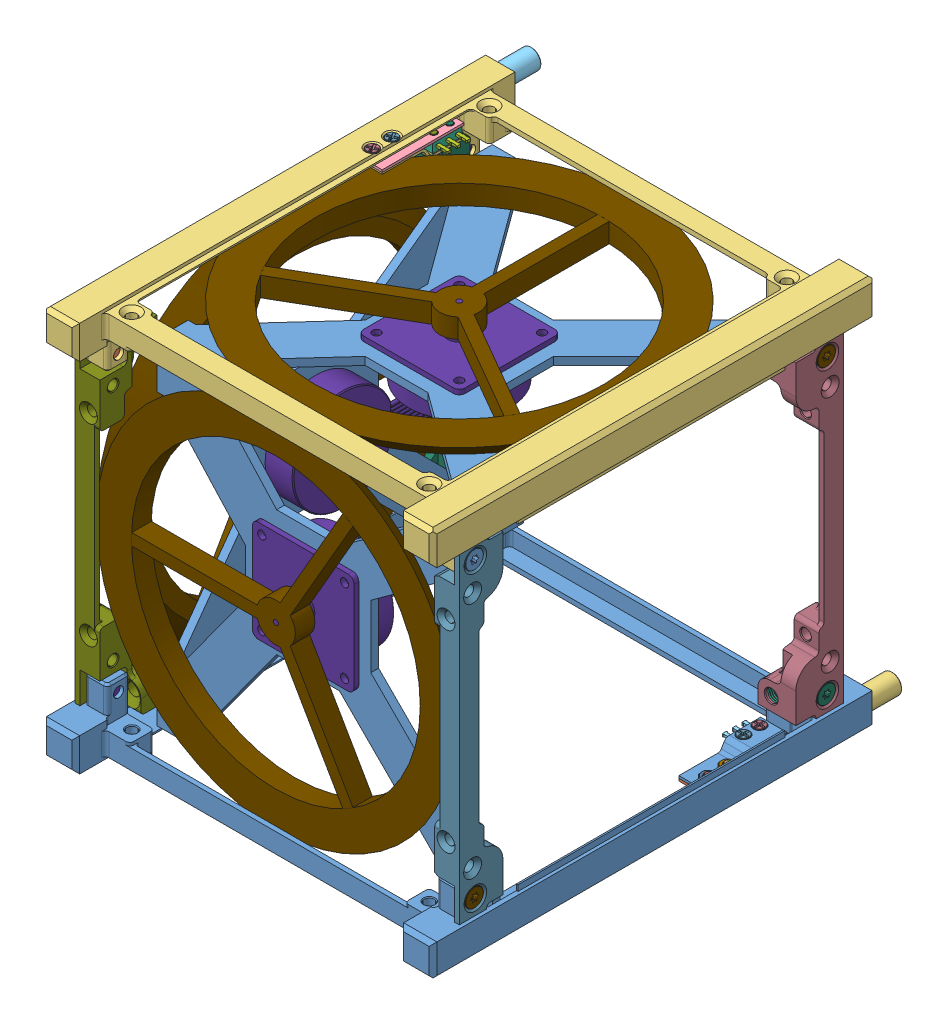
SolidWorks assembly 3dv1, configuration Default. Lengths in mm.
Overall size (100 100.02 121.5).
74 component instances, 55 part files, 12 mates.
Components (placement in the parent):
- isis_cubesat_sts_pc104_skeleton_asm-1: isis_cubesat_sts_pc104_skeleton_asm [Default] at (-72.5006 48.6232 32.8125) size (100 100.02 121.5)
  - INTEGRATED_SIDE_FRAME_007B-1: INTEGRATED_SIDE_FRAME_007B [Default] at origin size (100 15.41 121.5)
    - BRACKET_KS_007A-1: BRACKET_KS_007A [Default] at origin size (7.5 3.1 20.94)
    - BRACKET_KS_007B-1: BRACKET_KS_007B [Default] at origin size (7.5 0.6 20.94)
    - BUSJE_001-1: BUSJE_001 [Default] at origin size (5.05 5.05 11.8)
    - KILL_SWITCH_AV46J-1: KILL_SWITCH_AV46J [Default] at origin size (9.6 2.5 7.5)
      - KILL_SWITCH_BODY-1: KILL_SWITCH_BODY [Default] at origin size (6.6 2.5 7.5)
      - KILL_SWITCH_PINS-1: KILL_SWITCH_PINS [Default] at origin size (3.2 0.6 6.2)
    - KILL_SWITCH_LEVER-1: KILL_SWITCH_LEVER [Default] at origin size (4.59 2.4 6)
    - KILL_SWITCH_PIN-1: KILL_SWITCH_PIN [Default] at origin size (3.4 3.4 26.01)
    - KILL_SWITCH_SWITCH-1: KILL_SWITCH_SWITCH [Default] at origin size (2 1 1.2)
    - KS_MECH_SCREWS-1: KS_MECH_SCREWS [Default] at origin size (6.66 5 19.8)
      - NUT_M1_6-1: NUT_M1_6 [Default] at origin size (3.71 1.31 3.71)
      - NUT_M1_6_1-1: NUT_M1_6_1 [Default] at origin size (3.71 1.31 3.71)
      - SCREW_M1_6X4-1: SCREW_M1_6X4 [Default] at origin size (3 4.01 3)
      - SCREW_M1_6X4_1-1: SCREW_M1_6X4_1 [Default] at origin size (3 4.01 3)
      - SCREW_M1_6X4_2-1: SCREW_M1_6X4_2 [Default] at origin size (3 4.01 3)
      - SCREW_M1_6X4_3-1: SCREW_M1_6X4_3 [Default] at origin size (3 4.01 3)
    - SCREW_M2_5X6-1: SCREW_M2_5X6 [Default] at origin size (6.01 4.71 4.71)
    - SCREW_M2_5X6_1-1: SCREW_M2_5X6_1 [Default] at origin size (6.01 4.71 4.71)
    - SCREW_M2_5X6_2-1: SCREW_M2_5X6_2 [Default] at origin size (6.01 4.71 4.71)
    - SCREW_M2_5X6_3-1: SCREW_M2_5X6_3 [Default] at origin size (6.01 4.71 4.71)
    - SIDE_FRAME_007-1: SIDE_FRAME_007 [Default] at origin size (100 15.41 113.51)
    - SPRING_02-1: SPRING_02 [Default] at origin size (3.78 3.8 18.32)
  - INTEGRATED_SIDE_FRAME_007B_1-1: INTEGRATED_SIDE_FRAME_007B_1 [Default] at origin size (100 15.41 121.5)
    - BRACKET_KS_007A-1-1: BRACKET_KS_007A-1 [Default] at origin size (7.5 3.1 20.94)
    - BRACKET_KS_007B-1-1: BRACKET_KS_007B-1 [Default] at origin size (7.5 0.6 20.94)
    - BUSJE_001-1-1: BUSJE_001-1 [Default] at origin size (5.05 5.05 11.8)
    - KILL_SWITCH_AV46J-1-1: KILL_SWITCH_AV46J-1 [Default] at origin size (9.6 2.5 7.5)
      - KILL_SWITCH_BODY-1-1: KILL_SWITCH_BODY-1 [Default] at origin size (6.6 2.5 7.5)
      - KILL_SWITCH_PINS-1-1: KILL_SWITCH_PINS-1 [Default] at origin size (3.2 0.6 6.2)
    - KILL_SWITCH_LEVER-1-1: KILL_SWITCH_LEVER-1 [Default] at origin size (4.59 2.4 6)
    - KILL_SWITCH_PIN-1-1: KILL_SWITCH_PIN-1 [Default] at origin size (3.4 3.4 26.01)
    - KILL_SWITCH_SWITCH-1-1: KILL_SWITCH_SWITCH-1 [Default] at origin size (2 1 1.2)
    - KS_MECH_SCREWS-1-1: KS_MECH_SCREWS-1 [Default] at origin size (6.66 5 19.8)
      - NUT_M1_6-1-1: NUT_M1_6-1 [Default] at origin size (3.71 1.31 3.71)
      - NUT_M1_6_1-1-1: NUT_M1_6_1-1 [Default] at origin size (3.71 1.31 3.71)
      - SCREW_M1_6X4-1-1: SCREW_M1_6X4-1 [Default] at origin size (3 4.01 3)
      - SCREW_M1_6X4_1-1-1: SCREW_M1_6X4_1-1 [Default] at origin size (3 4.01 3)
      - SCREW_M1_6X4_2-1-1: SCREW_M1_6X4_2-1 [Default] at origin size (3 4.01 3)
      - SCREW_M1_6X4_3-1-1: SCREW_M1_6X4_3-1 [Default] at origin size (3 4.01 3)
    - SCREW_M2_5X6-1-1: SCREW_M2_5X6-1 [Default] at origin size (6.01 4.71 4.71)
    - SCREW_M2_5X6_1-1-1: SCREW_M2_5X6_1-1 [Default] at origin size (6.01 4.71 4.71)
    - SCREW_M2_5X6_2-1-1: SCREW_M2_5X6_2-1 [Default] at origin size (6.01 4.71 4.71)
    - SCREW_M2_5X6_3-1-1: SCREW_M2_5X6_3-1 [Default] at origin size (6.01 4.71 4.71)
    - SIDE_FRAME_007-1-1: SIDE_FRAME_007-1 [Default] at origin size (100 15.41 113.51)
    - SPRING_02-1-1: SPRING_02-1 [Default] at origin size (3.78 3.8 18.32)
  - REVE_02-1_ASSEMBLY_RIB_CDEF-1: REVE_02-1_ASSEMBLY_RIB_CDEF [Default] at origin size (98.4 86.8 98.4)
    - HELICOIL_M3_1_5D-1: HELICOIL_M3_1_5D [Default] at origin size (4 4 4.49)
      - MSBR-1-1: MSBR-1 [Default] at origin size (3.92 3.92 0.02)
      - MSBR-2-1: MSBR-2 [Default] at origin size (4 4 4.49)
    - HELICOIL_M3_1_5D_1-1: HELICOIL_M3_1_5D_1 [Default] at origin size (4 4 4.49)
      - MSBR-1-1-1: MSBR-1-1 [Default] at origin size (3.92 3.92 0.02)
      - MSBR-2-1-1: MSBR-2-1 [Default] at origin size (4 4 4.49)
    - HELICOIL_M3_1_5D_2-1: HELICOIL_M3_1_5D_2 [Default] at origin size (4 4 4.49)
      - MSBR-1-2-1: MSBR-1-2 [Default] at origin size (3.92 3.92 0.02)
      - MSBR-2-2-1: MSBR-2-2 [Default] at origin size (4 4 4.49)
    - HELICOIL_M3_1_5D_3-1: HELICOIL_M3_1_5D_3 [Default] at origin size (4 4 4.49)
      - MSBR-1-3-1: MSBR-1-3 [Default] at origin size (3.92 3.92 0.02)
      - MSBR-2-3-1: MSBR-2-3 [Default] at origin size (4 4 4.49)
    - REVD_02-1_RIB_D-1: REVD_02-1_RIB_D [Default] at origin size (9.7 82.8 12.2)
    - REVD_02-1_RIB_F-1: REVD_02-1_RIB_F [Default] at origin size (9.7 82.8 11.2)
    - REVE_02-1_RIB_C-1: REVE_02-1_RIB_C [Default] at origin size (9.8 86.8 12.2)
    - REVE_02-1_RIB_E-1: REVE_02-1_RIB_E [Default] at origin size (9.8 86.8 11.2)
- Assem14^3dv1-1: Assem14^3dv1 [Default] at (-23.745 -5.7749 128.5389) size (92 92 17.4) (virtual)
  - 2610T-1: 2610T [Default] at (1.2444 4.3981 -8.3764) size (37.25 26 17.4)
  - reaction wheel-1: reaction wheel [Default] at (1.2444 4.3981 3.0236) size (92 92 5)
- Assem14^3dv1-2: Assem14^3dv1 [Default] at (-61.477 -5.7749 88.3181) x (0 0 1) z (-1 0 0) size (92 92 17.4) (virtual)
  - 2610T-1: 2610T [Default] at (1.2444 4.3981 -8.3764) size (37.25 26 17.4)
  - reaction wheel-1: reaction wheel [Default] at (1.2444 4.3981 3.0236) size (92 92 5)
- Assem14^3dv1-3: Assem14^3dv1 [Default] at (-26.8987 38.3996 88.3181) x (0 0 1) z (0 1 0) size (92 92 17.4) (virtual)
  - 2610T-1: 2610T [Default] at (1.2444 4.3981 -8.3764) size (37.25 26 17.4)
  - reaction wheel-1: reaction wheel [Default] at (1.2444 4.3981 3.0236) size (92 92 5)
- Wheel Mount-1: Wheel Mount [Default] at (24.6994 38.1732 128.3125) x (0 0 -1) z (0 -1 0) size (85.95 85.95 85.95)
Mates (geometry in assembly coordinates):
- Width1: width: plane of Assem14^3dv1-1/2610T-1 through (-11.0006 11.6232 128.3125) normal (0 1 0); plane of Assem14^3dv1-1/2610T-1 through (-34.0006 -14.3768 128.3125) normal (0 -1 0); plane of isis_cubesat_sts_pc104_skeleton_asm-1/INTEGRATED_SIDE_FRAME_007B_1-1/SIDE_FRAME_007-1-1 through (20.6594 47.8232 37.3545) normal (0 1 0); plane of ? through (-65.6606 -50.5768 37.3545) normal (0 -1 0)
- Width2: width: plane of Assem14^3dv1-1/2610T-1 through (-9.5006 -12.8768 128.3125) normal (1 0 0); plane of Assem14^3dv1-1/2610T-1 through (-35.5006 10.1232 128.3125) normal (-1 0 0); plane of isis_cubesat_sts_pc104_skeleton_asm-1/REVE_02-1_ASSEMBLY_RIB_CDEF-1/REVE_02-1_RIB_E-1 through (-71.7006 41.6792 127.3385) normal (-1 0 0); plane of isis_cubesat_sts_pc104_skeleton_asm-1/REVE_02-1_ASSEMBLY_RIB_CDEF-1/REVD_02-1_RIB_F-1 through (26.6994 41.6792 138.9865) normal (1 0 0)
- Distance1: distance = 1 mm anti-aligned: plane of Assem14^3dv1-1/reaction wheel-1 through (-22.5006 -1.3768 136.5625) normal (0 0 1); plane of isis_cubesat_sts_pc104_skeleton_asm-1/REVE_02-1_ASSEMBLY_RIB_CDEF-1/REVD_02-1_RIB_F-1 through (21.5985 20.2552 137.5625) normal (0 0 -1)
- Width3: width: plane of Assem14^3dv1-3/2610T-1 through (-35.5006 38.1732 78.0625) normal (-1 0 0); plane of Assem14^3dv1-3/2610T-1 through (-9.5006 38.1732 101.0625) normal (1 0 0); plane of isis_cubesat_sts_pc104_skeleton_asm-1/INTEGRATED_SIDE_FRAME_007B_1-1/SIDE_FRAME_007-1-1 through (26.2994 47.6057 46.7145) normal (-1 0 0); plane of isis_cubesat_sts_pc104_skeleton_asm-1/INTEGRATED_SIDE_FRAME_007B_1-1/SIDE_FRAME_007-1-1 through (-71.3006 38.4407 132.4105) normal (1 0 0)
- Width4: width: plane of Assem14^3dv1-3/2610T-1 through (-11.0006 38.1732 76.5625) normal (0 0 -1); plane of Assem14^3dv1-3/2610T-1 through (-34.0006 38.1732 102.5625) normal (0 0 1); plane of isis_cubesat_sts_pc104_skeleton_asm-1/INTEGRATED_SIDE_FRAME_007B_1-1/SIDE_FRAME_007-1-1 through (-58.0686 42.6407 41.5625) normal (0 0 1); plane of isis_cubesat_sts_pc104_skeleton_asm-1/INTEGRATED_SIDE_FRAME_007B_1-1/SIDE_FRAME_007-1-1 through (13.0674 46.8057 137.5625) normal (0 0 -1)
- Distance2: distance = 1 mm anti-aligned: plane of Assem14^3dv1-3/reaction wheel-1 through (-22.5006 46.4232 89.5625) normal (0 1 0); plane of isis_cubesat_sts_pc104_skeleton_asm-1/INTEGRATED_SIDE_FRAME_007B_1-1/SIDE_FRAME_007-1-1 through (16.3034 47.4232 134.1785) normal (0 -1 0)
- Distance3: distance = 1 mm anti-aligned: plane of Assem14^3dv1-2/reaction wheel-1 through (-69.5006 -1.3768 89.5625) normal (-1 0 0); plane of isis_cubesat_sts_pc104_skeleton_asm-1/REVE_02-1_ASSEMBLY_RIB_CDEF-1/REVE_02-1_RIB_C-1 through (-70.5006 21.361 41.4567) normal (1 0 0)
- Width5: width: plane of Assem14^3dv1-2/2610T-1 through (-61.2506 -14.3768 78.0625) normal (0 -1 0); plane of Assem14^3dv1-2/2610T-1 through (-61.2506 11.6232 101.0625) normal (0 1 0); plane of ? through (-61.3046 -50.1768 134.1785) normal (0 1 0); plane of isis_cubesat_sts_pc104_skeleton_asm-1/INTEGRATED_SIDE_FRAME_007B_1-1/SIDE_FRAME_007-1-1 through (-71.4966 47.4232 134.1785) normal (0 -1 0)
- Width6: width: plane of Assem14^3dv1-2/2610T-1 through (-61.2506 10.1232 76.5625) normal (0 0 -1); plane of Assem14^3dv1-2/2610T-1 through (-61.2506 -12.8768 102.5625) normal (0 0 1); plane of isis_cubesat_sts_pc104_skeleton_asm-1/REVE_02-1_ASSEMBLY_RIB_CDEF-1/REVE_02-1_RIB_E-1 through (-66.5949 -23.0088 137.5625) normal (0 0 -1); plane of isis_cubesat_sts_pc104_skeleton_asm-1/REVE_02-1_ASSEMBLY_RIB_CDEF-1/REVE_02-1_RIB_C-1 through (-66.5947 20.2552 41.5625) normal (0 0 1)
- Coincident3: coincident anti-aligned: plane of Assem14^3dv1-1/2610T-1 through (-34.0006 -12.8768 128.3125) normal (0 0 -1); plane of Wheel Mount-1 through (24.6994 -47.7768 128.3125) normal (0 0 1)
- Coincident4: coincident anti-aligned: plane of Assem14^3dv1-3/2610T-1 through (-34.0006 38.1732 78.0625) normal (0 -1 0); plane of Wheel Mount-1 through (-61.2506 38.1732 128.3125) normal (0 1 0)
- Coincident5: coincident anti-aligned: plane of Assem14^3dv1-2/2610T-1 through (-61.2506 -12.8768 78.0625) normal (1 0 0); plane of Wheel Mount-1 through (-61.2506 -47.7768 128.3125) normal (-1 0 0)
